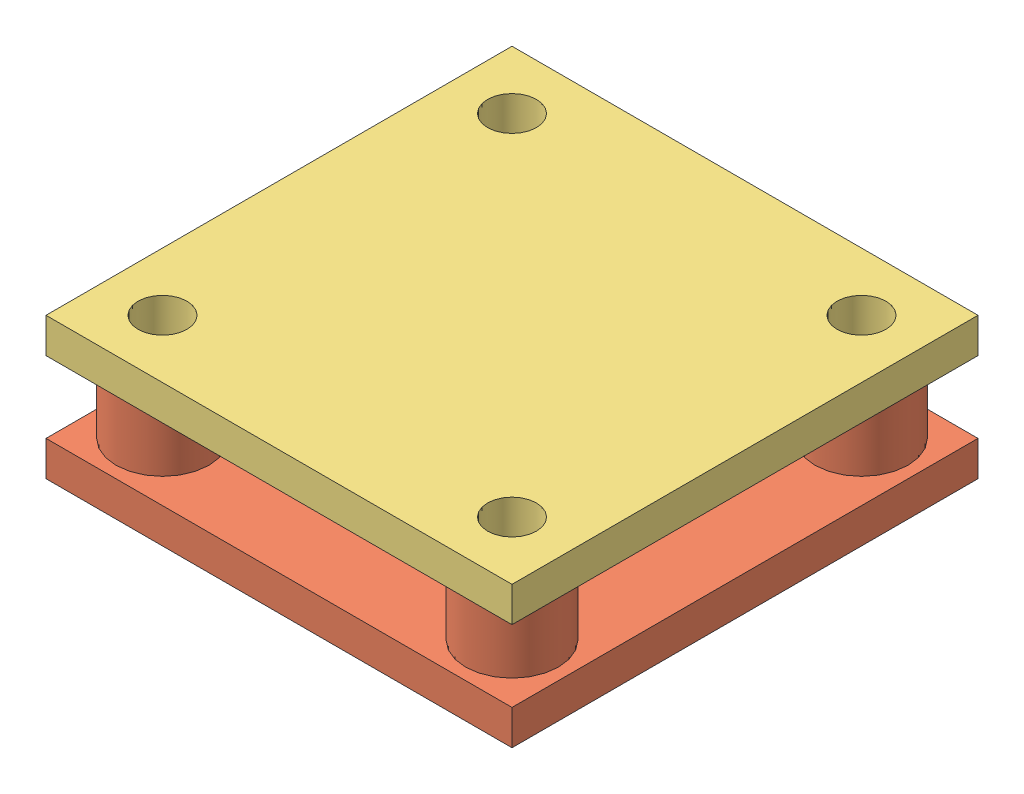
SolidWorks assembly BNO055 Assembly, configuration 預設. Lengths in mm.
Overall size (40 12.15 40).
3 component instances, 3 part files, 7 mates.
Components (placement in the parent):
- Adafruit_BNO055-1: Adafruit_BNO055 [Default] at origin size (26.67 4.2 20.32)
- BNO055 Bottom Case-1: BNO055 Bottom Case [預設] at (13.335 -5 -10.16) x (0 0 1) z (0 1 0) size (40 40 9.15)
- BNO055 Top Case-1: BNO055 Top Case [預設] at (13.335 7.15 -10.16) x (0 0 -1) z (0 -1 0) size (40 40 7.15)
Mates (geometry in assembly coordinates):
- 同軸心3: concentric aligned: cylinder of Adafruit_BNO055-1 through (24.13 1.65 -17.78) axis (0 -1 0) radius 1.25; cylinder of BNO055 Bottom Case-1 through (24.13 4.15 -17.78) axis (0 -1 0) radius 0.9
- 同軸心4: concentric aligned: cylinder of Adafruit_BNO055-1 through (2.54 1.65 -2.54) axis (0 -1 0) radius 1.25; cylinder of BNO055 Bottom Case-1 through (2.54 4.15 -2.54) axis (0 -1 0) radius 0.9
- 重合/共線/共點1: coincident anti-aligned: plane of Adafruit_BNO055-1 through (24.13 0 -2.54) normal (0 -1 0); plane of BNO055 Bottom Case-1 through (2.54 0 -2.54) normal (0 1 0)
- 同軸心6: concentric aligned: cylinder of BNO055 Bottom Case-1 through (24.13 4.15 -17.78) axis (0 -1 0) radius 0.9; cylinder of BNO055 Top Case-1 through (24.13 4.15 -17.78) axis (0 -1 0) radius 1.25
- 同軸心7: concentric aligned: cylinder of BNO055 Bottom Case-1 through (2.54 4.15 -2.54) axis (0 -1 0) radius 0.9; cylinder of BNO055 Top Case-1 through (2.54 4.15 -2.54) axis (0 -1 0) radius 1.25
- 重合/共線/共點2: coincident anti-aligned: plane of BNO055 Bottom Case-1 through (2.54 4.15 -17.78) normal (0 1 0); plane of BNO055 Top Case-1 through (2.54 4.15 -17.78) normal (0 -1 0)
- 重合/共線/共點3: coordinate: point of Adafruit_BNO055-1
